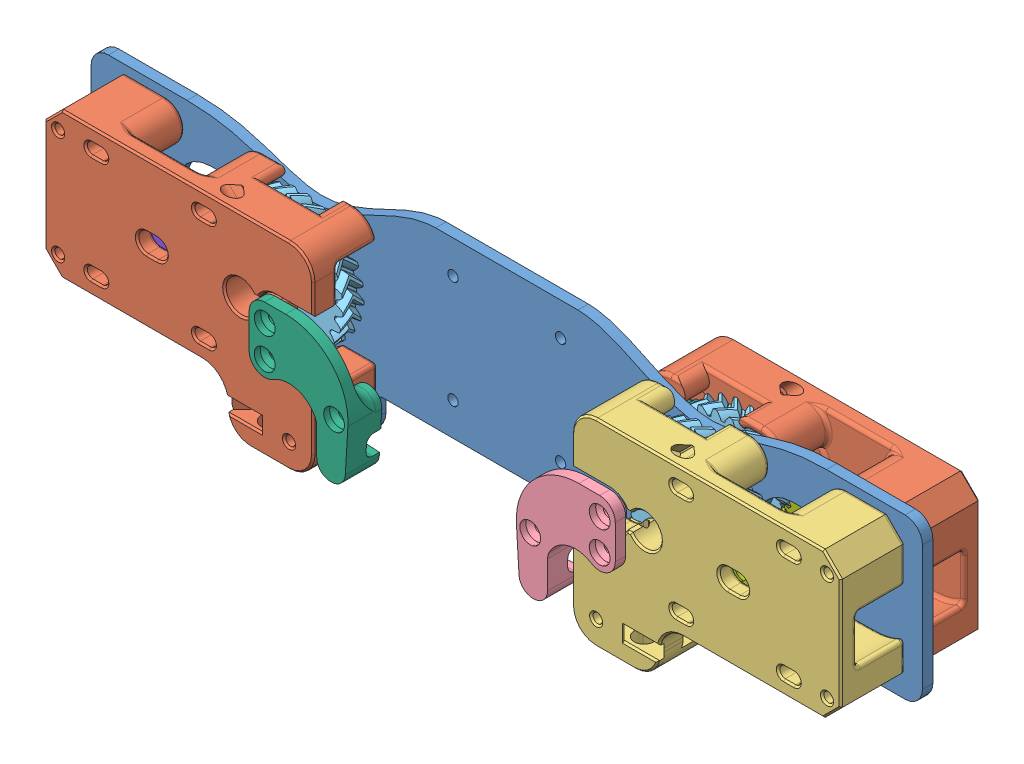
SolidWorks assembly TriColour, configuration Default. Lengths in mm.
Overall size (239.5 63 46).
13 component instances, 8 part files, 33 mates.
Components (placement in the parent):
- mendel mount tri colour-1: mendel mount tri colour [Default] at (-239.5 50 0) x (1 0 0) z (0 0 -1) size (239.5 62.5 3)
- 1306M-1: 1306M [Default] at (-203 23 9.9) x (0 -1 0) z (0 0 1) size (57.6 77.5 18.81)
- 1306M-2: 1306M [Default] at (-36.5 23 -12.9) x (0 -1 0) z (0 0 -1) size (57.6 77.5 18.81)
- 1306-1: 1306 [Default] at (-36.5 23 18.5) x (0 -1 0) z (0 0 -1) size (57.6 77.5 18.81)
- 1309-1: 1309 [Default] at (-71.5 23.0557 18.5) x (-1 0 0) z (0 0 1) size (28.5 35.3 9.8)
- 1311-1: 1311 [ISO - RH Helical gear 1M 17T 45HA 20PA 12FW ---17A75H50L0.8N] at (-61.5 23 1) x (0 0 1) z (-1 0 0) size (9 36.33 36.3)
- 1311-2: 1311 [ISO - RH Helical gear 1M 17T 45HA 20PA 12FW ---17A75H50L0.8N] at (-178 23 1) x (0 0 1) z (-1 0 0) size (9 36.33 36.3)
- 1311-3: 1311 [ISO - RH Helical gear 1M 17T 45HA 20PA 12FW ---17A75H50L0.8N] at (-61.5 23 -4) x (0 0 -1) z (1 0 0) size (9 36.33 36.3)
- 1309M-1: 1309M [Default] at (-168 23.0557 24.5) x (1 0 0) z (0 0 -1) size (28.5 35.3 9.8)
- 1309M-2: 1309M [Default] at (-71.5 23.0557 -27.5) x (-1 0 0) z (0 0 1) size (28.5 35.3 9.8)
- 1310.1-1: 1310.1 [ISO - RH Helical gear 1M 17T 45HA 20PA 12FW ---17A75H50L0.8N] at (-37.5 23 -7.5) x (0 0 -1) z (-0.923728 -0.383049 0) size (13 17.1 17.1)
- 1310.1-2: 1310.1 [ISO - RH Helical gear 1M 17T 45HA 20PA 12FW ---17A75H50L0.8N] at (-37.5 23 4.5) x (0 0 1) z (-0.809083 -0.587695 0) size (13 17.1 17.1)
- 1310-2: 1310 [ISO - RH Helical gear 1M 17T 45HA 20PA 12FW ---17A75H50L0.8N] at (-202 23 4.5) x (0 0 1) z (0.923728 0.383049 0) size (25.5 17.1 17.1)
Mates (geometry in assembly coordinates):
- Coincident3: coincident anti-aligned: plane of mendel mount tri colour-1 through (-239.5 0 -3) normal (0 -1 0); plane of assembly through (0 0 0) normal (0 1 0)
- Coincident4: coincident aligned: plane of mendel mount tri colour-1 through (-239.5 50 0) normal (0 0 1); plane of assembly through (0 0 0) normal (0 0 1)
- Coincident5: coincident aligned: plane of mendel mount tri colour-1 through (0 50 -3) normal (1 0 0); plane of assembly through (0 0 0) normal (1 0 0)
- Concentric1: concentric anti-aligned: cylinder of mendel mount tri colour-1 through (-164 -6 -26.2941) axis (0 0 1) radius 1.4; cylinder of 1306M-1 through (-164 -6 18.5) axis (0 0 -1) radius 1.4
- Concentric2: concentric aligned: cylinder of mendel mount tri colour-1 through (-230.5 38.5 -3) axis (0 0 1) radius 1.5; cylinder of 1306M-1 through (-230.5 38.5 7) axis (0 0 1) radius 1.4
- Coincident6: coincident anti-aligned: plane of mendel mount tri colour-1 through (-239.5 50 0) normal (0 0 1); plane of 1306M-1 through (-203 23 0) normal (0 0 -1)
- Concentric3: concentric aligned: cylinder of mendel mount tri colour-1 through (-75.5 -6 -26.2941) axis (0 0 1) radius 1.4; cylinder of 1306M-2 through (-75.5 -6 -21.5) axis (0 0 1) radius 1.4
- Coincident7: coincident anti-aligned: plane of mendel mount tri colour-1 through (-239.5 50 -3) normal (0 0 -1); plane of 1306M-2 through (-36.5 23 -3) normal (0 0 1)
- Concentric4: concentric aligned: circle of mendel mount tri colour-1; cylinder of 1306M-2 through (-9 7.5 -10) axis (0 0 -1) radius 1.4
- Coincident8: coincident anti-aligned: plane of mendel mount tri colour-1 through (-239.5 50 0) normal (0 0 1); plane of 1306-1 through (-36.5 23 0) normal (0 0 -1)
- Concentric6: concentric anti-aligned: cylinder of mendel mount tri colour-1 through (-75.5 -6 -26.2941) axis (0 0 1) radius 1.4; cylinder of 1306-1 through (-75.5 -6 18.5) axis (0 0 -1) radius 1.4
- Concentric7: concentric aligned: cylinder of mendel mount tri colour-1 through (-9 38.5 -3) axis (0 0 1) radius 1.5; cylinder of 1306-1 through (-9 38.5 7) axis (0 0 1) radius 1.4
- Concentric8: concentric anti-aligned: cylinder of 1306-1 through (-71.5 14.0557 0) axis (0 0 1) radius 1.7; cylinder of 1309-1 through (-71.5 14.0557 21.5) axis (0 0 -1) radius 1.4
- Parallel2: parallel anti-aligned: plane of 1306-1 through (-82.5 17.5 7) normal (-1 0 0); plane of 1309-1 through (-86.5 5.0557 21.5) normal (1 0 0)
- Coincident10: coincident anti-aligned: plane of 1306-1 through (-71.5803 23 18.5) normal (0 0 1); plane of 1309-1 through (-71.5 23.8557 18.5) normal (0 0 -1)
- Coincident11: coincident anti-aligned: plane of 1306-1 through (-71.5803 23 7) normal (0 0 -1); plane of 1311-1 through (-61.5 23 7) normal (0 0 1)
- Concentric9: concentric anti-aligned: cylinder of 1306-1 through (-61.5 23 7) axis (0 0 1) radius 4.6; circle of 1311-1
- Coincident12: coincident anti-aligned: plane of 1306M-1 through (-167.9197 23 7) normal (0 0 -1); plane of 1311-2 through (-178 23 7) normal (0 0 1)
- Concentric10: concentric anti-aligned: cylinder of 1306M-1 through (-178 23 7) axis (0 0 1) radius 4.6; circle of 1311-2
- Coincident14: coincident anti-aligned: plane of 1306M-2 through (-71.5803 23 -10) normal (0 0 1); plane of 1311-3 through (-61.5 23 -10) normal (0 0 -1)
- Concentric11: concentric anti-aligned: cylinder of 1306M-2 through (-61.5 23 -10) axis (0 0 -1) radius 4.6; cylinder of 1311-3 through (-61.5 23 -10) axis (0 0 1) radius 1.65
- Concentric12: concentric anti-aligned: cylinder of 1306M-2 through (-71.5 14.0557 -3) axis (0 0 -1) radius 1.7; circle of 1309M-2
- Coincident15: coincident anti-aligned: plane of 1306M-2 through (-71.5803 23 -21.5) normal (0 0 -1); plane of 1309M-2 through (-71.5 23.8557 -21.5) normal (0 0 1)
- Parallel3: parallel anti-aligned: plane of 1306M-2 through (-82.5 17.5 -10) normal (-1 0 0); plane of 1309M-2 through (-86.5 5.0557 -24.5) normal (1 0 0)
- Concentric13: concentric anti-aligned: cylinder of 1306M-1 through (-168 14.0557 0) axis (0 0 1) radius 1.7; cylinder of 1309M-1 through (-168 14.0557 21.5) axis (0 0 -1) radius 1.4
- Coincident17: coincident anti-aligned: plane of 1306M-1 through (-167.9197 23 18.5) normal (0 0 1); plane of 1309M-1 through (-168 23.8557 18.5) normal (0 0 -1)
- Parallel4: parallel anti-aligned: plane of 1306M-1 through (-157 17.5 7) normal (1 0 0); plane of 1309M-1 through (-153 5.0557 21.5) normal (-1 0 0)
- Concentric14: concentric aligned: cylinder of 1306M-1 through (-202 23 7) axis (0 0 1) radius 2.75; cylinder of 1310-2 through (-202 23 1) axis (0 0 1) radius 2.7
- Coincident19: coincident anti-aligned: plane of 1306M-1 through (-167.9197 23 14) normal (0 0 -1); plane of 1310-2 through (-202 23 14) normal (0 0 1)
- Concentric15: concentric aligned: cylinder of 1306M-2 through (-37.5 23 -10) axis (0 0 -1) radius 2.75; cylinder of 1310.1-1 through (-37.5 23 -4) axis (0 0 -1) radius 2.7
- Coincident20: coincident anti-aligned: plane of 1306M-2 through (-71.5803 23 -17) normal (0 0 1); plane of 1310.1-1 through (-37.5 23 -17) normal (0 0 -1)
- Concentric16: concentric anti-aligned: cylinder of 1306M-2 through (-37.5 23 -10) axis (0 0 -1) radius 2.75; cylinder of 1310.1-2 through (-37.5 23 1) axis (0 0 1) radius 2.7
- Coincident21: coincident anti-aligned: plane of 1306-1 through (-71.5803 23 14) normal (0 0 -1); plane of 1310.1-2 through (-37.5 23 14) normal (0 0 1)
